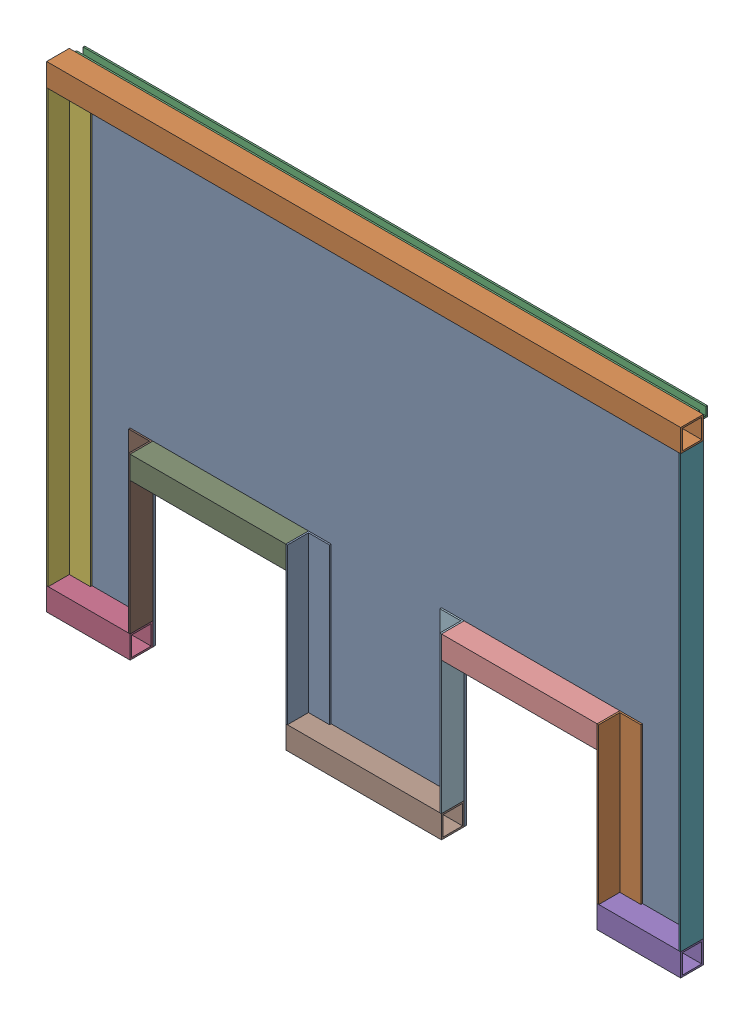
SolidWorks assembly GE-16003_ASM, configuration Default. Lengths in mm.
Overall size (1241.42 933.45 63.5).
14 component instances, 7 part files, 0 mates.
Components (placement in the parent):
- GE-16003-01-1: GE-16003-01 [Default] at origin size (1219.2 914.4 4.76)
- GE-16003-02-1: GE-16003-02 [Default] at (0 454.025 24.6062) size (1241.42 44.45 44.45)
- GE-16003-03-1: GE-16003-03 [Default] at (0 466.725 -7.1437) x (1 0 0) z (0 0 -1) size (1219.2 19.05 19.05)
- GE-16003-04-1: GE-16003-04 [Default] at (-538.9563 -434.975 24.6062) size (163.51 44.45 44.45)
- GE-16003-04-2: GE-16003-04 [Default] at (538.9563 -434.975 24.6062) size (163.51 44.45 44.45)
- GE-16003-05-1: GE-16003-05 [Default] at (-620.7125 9.525 2.3813) x (0 -1 0) z (0 0 -1) size (844.55 44.45 44.45)
- GE-16003-05-2: GE-16003-05 [Default] at (620.7125 9.525 2.3813) x (0 -1 0) z (1 0 0) size (844.55 44.45 44.45)
- GE-16003-06-1: GE-16003-06 [Default] at (0 -434.975 24.6062) size (304.8 44.45 44.45)
- GE-16003-06-2: GE-16003-06 [Default] at (-304.8 -130.175 24.6062) size (304.8 44.45 44.45)
- GE-16003-06-3: GE-16003-06 [Default] at (304.8 -130.175 24.6062) size (304.8 44.45 44.45)
- GE-16003-07-1: GE-16003-07 [Default] at (-457.2 -260.35 2.3813) x (0 -1 0) z (1 0 0) size (304.8 44.45 44.45)
- GE-16003-07-2: GE-16003-07 [Default] at (152.4 -260.35 2.3813) x (0 -1 0) z (1 0 0) size (304.8 44.45 44.45)
- GE-16003-07-3: GE-16003-07 [Default] at (-152.4 -260.35 2.3813) x (0 1 0) z (-1 0 0) size (304.8 44.45 44.45)
- GE-16003-07-4: GE-16003-07 [Default] at (457.2 -260.35 2.3813) x (0 1 0) z (-1 0 0) size (304.8 44.45 44.45)
